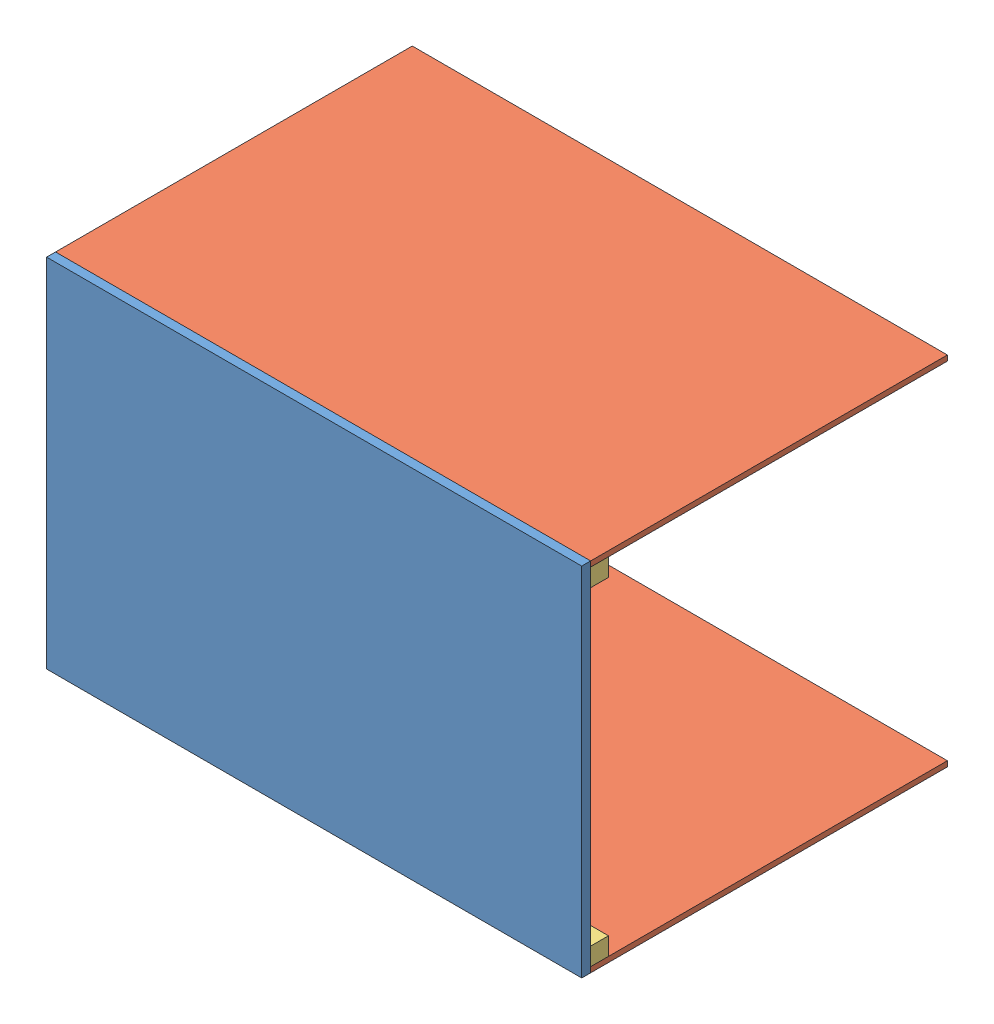
SolidWorks assembly Assemblage1, configuration Défaut. Lengths in mm.
Overall size (300 200 205).
5 component instances, 3 part files, 10 mates.
Components (placement in the parent):
- sol-1: sol [Défaut] at (-159.1545 -67.5742 300) size (300 200 5)
- mur 2-1: mur 2 [Défaut] at (-167.4478 122.2064 115.193) x (1 0 0) z (0 -1 0) size (300 200 3)
- fixation-2: fixation [Défaut] at (-163.9294 108.4068 290) size (300 10 10)
- mur 2-2: mur 2 [Défaut] at (-167.4478 -74.7936 115.193) x (1 0 0) z (0 -1 0) size (300 200 3)
- fixation-3: fixation [Défaut] at (-163.9294 -75.5932 290) size (300 10 10)
Mates (geometry in assembly coordinates):
- Coïncidente5: coincident aligned: line of sol-1 through (73.0039 122.2064 300) axis (-1 0 0); line of mur 2-1 through (73.0039 122.2064 300) axis (-1 0 0)
- Coïncidente7: coincident: point of sol-1; point of mur 2-1
- Coïncidente8: coincident anti-aligned: plane of mur 2-1 through (-167.4478 119.2064 115.193) normal (0 -1 0); plane of fixation-2 through (-226.9961 119.2064 300) normal (0 1 0)
- Coïncidente9: coincident: point of mur 2-1; point of fixation-2
- Coïncidente10: coincident aligned: line of sol-1 through (73.0039 -77.7936 300) axis (0 1 0); line of fixation-2 through (73.0039 109.2064 300) axis (0 1 0)
- Coïncidente11: coincident anti-aligned: line of sol-1 through (-226.9961 -77.7936 300) axis (1 0 0); line of mur 2-2 through (73.0039 -77.7936 300) axis (-1 0 0)
- Coïncidente13: coincident: point of sol-1; line of mur 2-2 through (-226.9961 -77.7936 300) axis (0 0.970213 -0.242254)
- Coïncidente14: coincident anti-aligned: plane of mur 2-2 through (-167.4478 -119.6533 119.9711) normal (0 0.970213 -0.242254); plane of fixation-3 through (-226.9961 -74.8829 299.2732) normal (0 -0.970213 0.242254)
- Coïncidente16: coincident: point of mur 2-2; point of fixation-3
- Coïncidente17: coincident anti-aligned: plane of sol-1 through (-159.1545 -67.5742 300) normal (0 0 -1); plane of fixation-3 through (-163.9294 -75.5932 300) normal (0 0 1)
